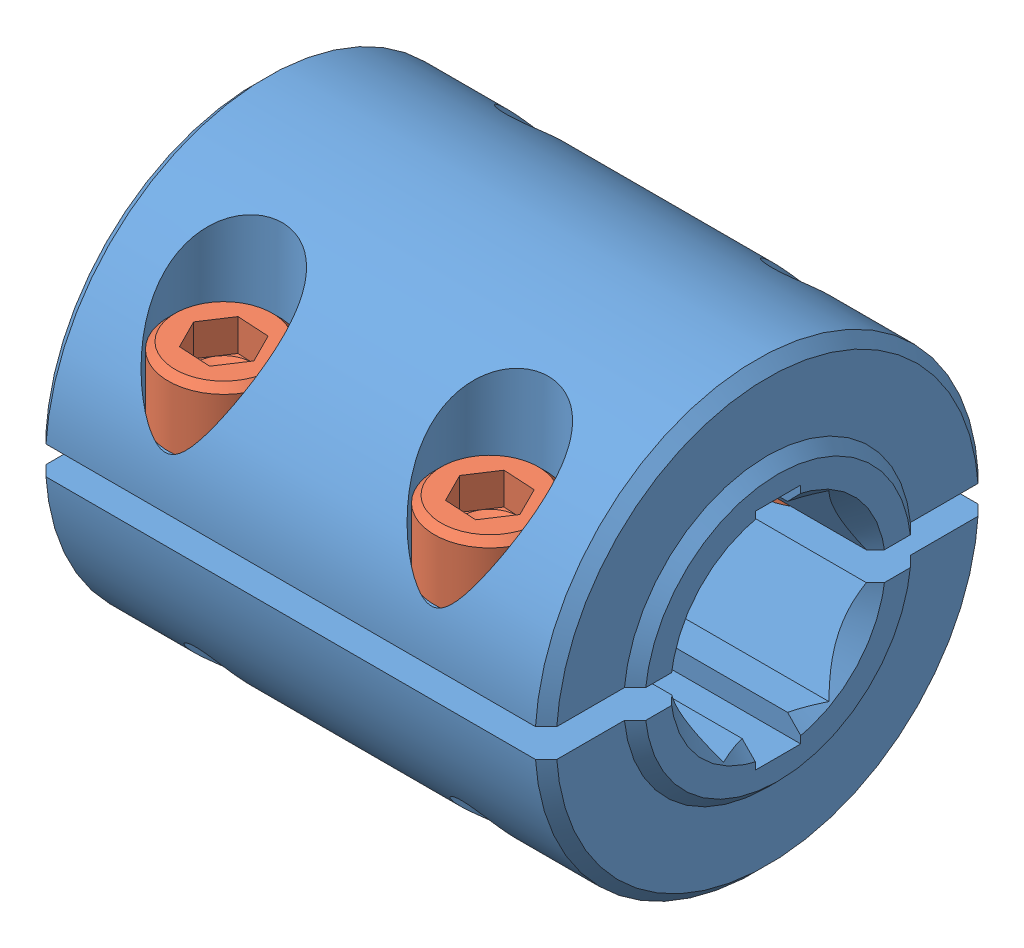
SolidWorks assembly am-1560 500Hex and 500Key Coupler.STEP, configuration Default. Lengths in mm.
Overall size (38.1 31.75 31.68).
6 component instances, 2 part files, 0 mates.
Components (placement in the parent):
- 500Hex and Key Coupler.STEP-1: 500Hex and Key Coupler.STEP [Default] at (19.05 1.016 15.8425) x (0 0 1) z (-1 0 0) size (31.68 14.86 38.1)
- 500Hex and Key Coupler.STEP-2: 500Hex and Key Coupler.STEP [Default] at (19.05 1.016 15.8425) x (0 0 -1) z (-1 0 0) size (31.68 14.86 38.1)
- 10-32x0500_shcs_HX-SHCS 0.19-32x1.375x1-C.STEP-1: 10-32x0500_shcs_HX-SHCS 0.19-32x1.375x1-C.STEP [Default] at (9.525 -8.001 4.73) x (0 1 0) z (-0.057029 0 0.998373) size (17.53 7.94 7.94)
- 10-32x0500_shcs_HX-SHCS 0.19-32x1.375x1-C.STEP-2: 10-32x0500_shcs_HX-SHCS 0.19-32x1.375x1-C.STEP [Default] at (28.575 -8.001 4.73) x (0 1 0) z (-0.057029 0 0.998373) size (17.53 7.94 7.94)
- 10-32x0500_shcs_HX-SHCS 0.19-32x1.375x1-C.STEP-3: 10-32x0500_shcs_HX-SHCS 0.19-32x1.375x1-C.STEP [Default] at (28.575 10.033 26.955) x (0 -1 0) z (-0.057029 0 0.998373) size (17.53 7.94 7.94)
- 10-32x0500_shcs_HX-SHCS 0.19-32x1.375x1-C.STEP-4: 10-32x0500_shcs_HX-SHCS 0.19-32x1.375x1-C.STEP [Default] at (9.525 10.033 26.955) x (0 -1 0) z (-0.057029 0 0.998373) size (17.53 7.94 7.94)
